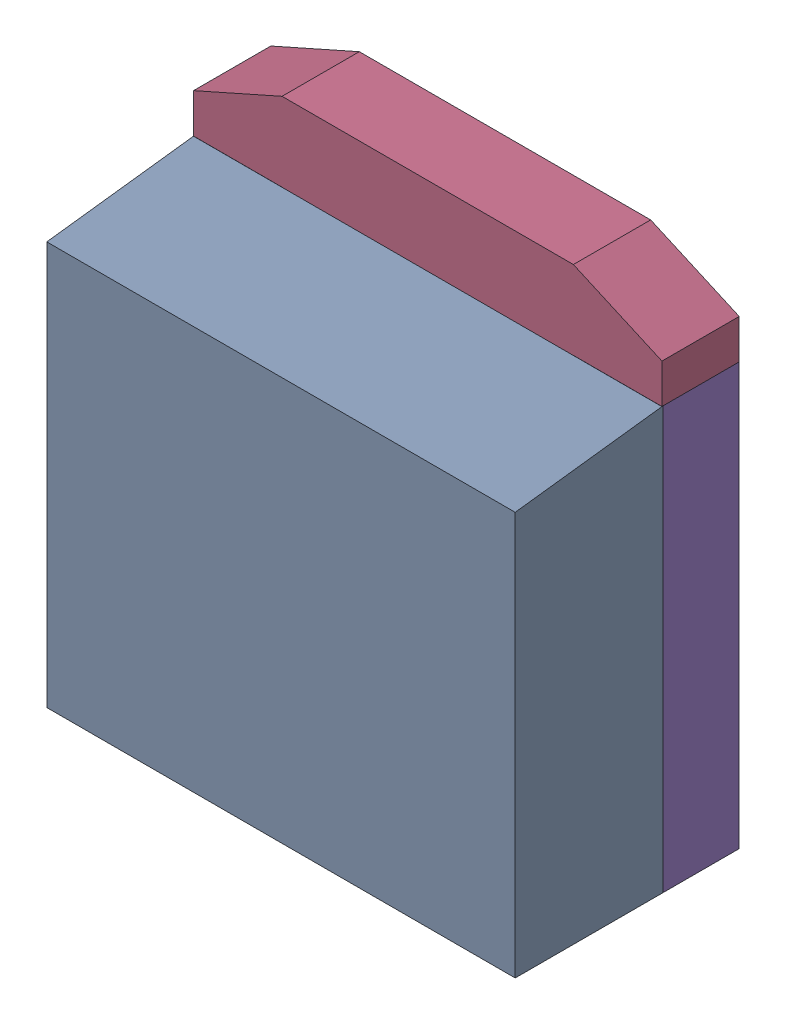
SolidWorks assembly SW3dPS-TO263-3S_Free-Models7, configuration Default. Lengths in mm.
Overall size (10 10.68 4.78).
12 component instances, 5 part files, 0 mates.
Components (placement in the parent):
- SW3dPS-TO263-3S_BODY4-1: SW3dPS-TO263-3S_BODY4 [Default] at (0.0127 0 1.5827) x (0 0 1) z (-1 0 0) size (3.15 9 10)
  - SW3dPS-TO263-3S_Free-Models8-1: SW3dPS-TO263-3S_Free-Models8 [Default] at origin size (3.15 9 10)
    - SW3dPS-TO263-3S_453496017-1: SW3dPS-TO263-3S_453496017 [Default] at (0 4.4 -4.9873) size (3.15 9 10)
      - SW3dPS-TO263-3S_Extruded18-1: SW3dPS-TO263-3S_Extruded18 [Default] at origin size (3.15 9 10)
  - SW3dPS-TO263-3S_Board7-1: SW3dPS-TO263-3S_Board7 [Default] at (0 0 -0.0938) size (0.01 0.01 0.11)
- SW3dPS-TO263-3S_BODY5-1: SW3dPS-TO263-3S_BODY5 [Default] at (0 0 0.0127) size (10 10.68 1.65)
  - SW3dPS-TO263-3S_Board6-1: SW3dPS-TO263-3S_Board6 [Default] at (0 0 -0.0938) size (0.01 0.01 0.11)
  - SW3dPS-TO263-3S_Free-Models9-1: SW3dPS-TO263-3S_Free-Models9 [Default] at origin size (10 10.68 1.65)
    - SW3dPS-TO263-3S_453494353-1: SW3dPS-TO263-3S_453494353 [Default] at (0 7.15 -1.6373) size (10 6.86 1.65)
      - SW3dPS-TO263-3S_Extruded15-1: SW3dPS-TO263-3S_Extruded15 [Default] at origin size (10 6.86 1.65)
    - SW3dPS-TO263-3S_453494225-1: SW3dPS-TO263-3S_453494225 [Default] at (0 4.4 -1.6373) size (10 9 1.65)
      - SW3dPS-TO263-3S_Extruded17-1: SW3dPS-TO263-3S_Extruded17 [Default] at origin size (10 9 1.65)
